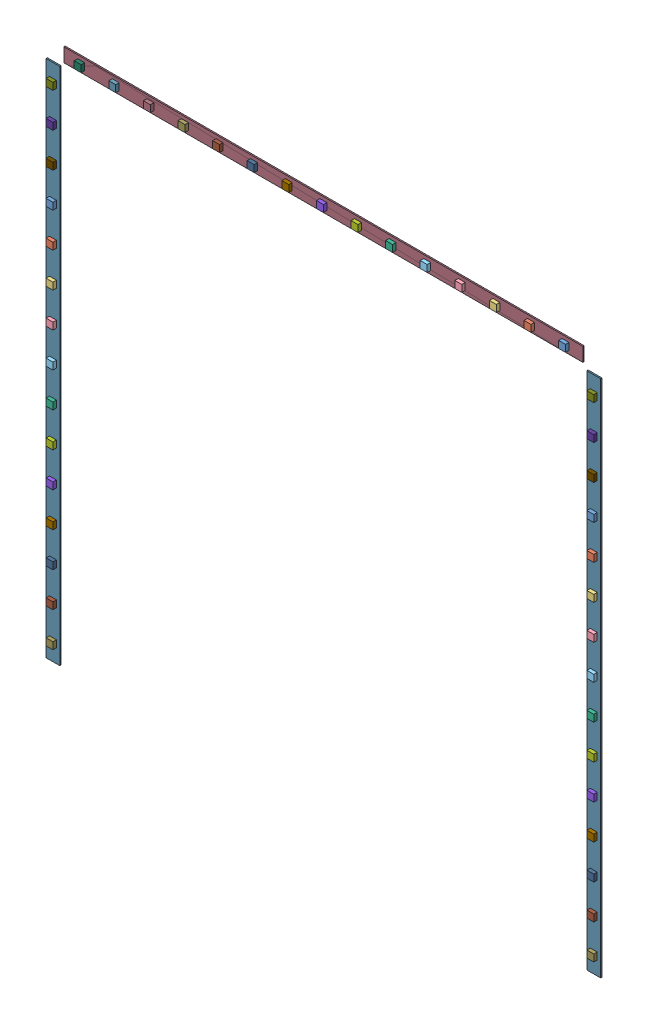
SolidWorks assembly 1161-B2P-D, configuration По умолчанию. Lengths in mm.
Overall size (320.63 311.01 2.75).
49 component instances, 32 part files, 0 mates.
Components (placement in the parent):
- 1_1-1: 1_1 [По умолчанию] at origin size (4 4 2)
- 2_1-1: 2_1 [По умолчанию] at origin size (4 4 2)
- 3_1-1: 3_1 [По умолчанию] at origin size (4 4 2)
- 4_1-1: 4_1 [По умолчанию] at origin size (4 4 2)
- 5_1-1: 5_1 [По умолчанию] at origin size (4 4 2)
- 6-1: 6 [По умолчанию] at origin size (4 4 2)
- 7-1: 7 [По умолчанию] at origin size (4 4 2)
- 8-1: 8 [По умолчанию] at origin size (4 4 2)
- 9-1: 9 [По умолчанию] at origin size (4 4 2)
- 10-1: 10 [По умолчанию] at origin size (4 4 2)
- 11-1: 11 [По умолчанию] at origin size (4 4 2)
- 12-1: 12 [По умолчанию] at origin size (4 4 2)
- 13-1: 13 [По умолчанию] at origin size (4 4 2)
- 14-1: 14 [По умолчанию] at origin size (4 4 2)
- 15-1: 15 [По умолчанию] at origin size (4 4 2)
- 16-1: 16 [По умолчанию] at origin size (4 4 2)
- 17-1: 17 [По умолчанию] at origin size (4 4 2)
- 18-1: 18 [По умолчанию] at origin size (4 4 2)
- 19-1: 19 [По умолчанию] at origin size (4 4 2)
- 20-1: 20 [По умолчанию] at origin size (4 4 2)
- 21-1: 21 [По умолчанию] at origin size (4 4 2)
- 22-1: 22 [По умолчанию] at origin size (4 4 2)
- 23-1: 23 [По умолчанию] at origin size (4 4 2)
- 24-1: 24 [По умолчанию] at origin size (4 4 2)
- 25-1: 25 [По умолчанию] at origin size (4 4 2)
- 26-1: 26 [По умолчанию] at origin size (4 4 2)
- 27-1: 27 [По умолчанию] at origin size (4 4 2)
- 28-1: 28 [По умолчанию] at origin size (4 4 2)
- 29-1: 29 [По умолчанию] at origin size (4 4 2)
- 30-1: 30 [По умолчанию] at origin size (4 4 2)
- 31-1: 31 [По умолчанию] at origin size (300 8 0.75)
- 32-1: 32 [По умолчанию] at origin size (8 300 0.75)
- 32-2: 32 [По умолчанию] at (0 0 0.75) x (-1 0 0) z (0 0 -1) size (8 300 0.75)
- 31-2: 31 [По умолчанию] at (0 0 0.75) x (-1 0 0) z (0 0 -1) size (300 8 0.75)
- 30-2: 30 [По умолчанию] at (0 0 3.5) x (-1 0 0) z (0 0 -1) size (4 4 2)
- 29-2: 29 [По умолчанию] at (0 0 3.5) x (-1 0 0) z (0 0 -1) size (4 4 2)
- 28-2: 28 [По умолчанию] at (0 0 3.5) x (-1 0 0) z (0 0 -1) size (4 4 2)
- 27-2: 27 [По умолчанию] at (0 0 3.5) x (-1 0 0) z (0 0 -1) size (4 4 2)
- 26-2: 26 [По умолчанию] at (0 0 3.5) x (-1 0 0) z (0 0 -1) size (4 4 2)
- 25-2: 25 [По умолчанию] at (0 0 3.5) x (-1 0 0) z (0 0 -1) size (4 4 2)
- 24-2: 24 [По умолчанию] at (0 0 3.5) x (-1 0 0) z (0 0 -1) size (4 4 2)
- 23-2: 23 [По умолчанию] at (0 0 3.5) x (-1 0 0) z (0 0 -1) size (4 4 2)
- 22-2: 22 [По умолчанию] at (0 0 3.5) x (-1 0 0) z (0 0 -1) size (4 4 2)
- 21-2: 21 [По умолчанию] at (0 0 3.5) x (-1 0 0) z (0 0 -1) size (4 4 2)
- 20-2: 20 [По умолчанию] at (0 0 3.5) x (-1 0 0) z (0 0 -1) size (4 4 2)
- 19-2: 19 [По умолчанию] at (0 0 3.5) x (-1 0 0) z (0 0 -1) size (4 4 2)
- 18-2: 18 [По умолчанию] at (0 0 3.5) x (-1 0 0) z (0 0 -1) size (4 4 2)
- 17-2: 17 [По умолчанию] at (0 0 3.5) x (-1 0 0) z (0 0 -1) size (4 4 2)
- 16-2: 16 [По умолчанию] at (0 0 3.5) x (-1 0 0) z (0 0 -1) size (4 4 2)
